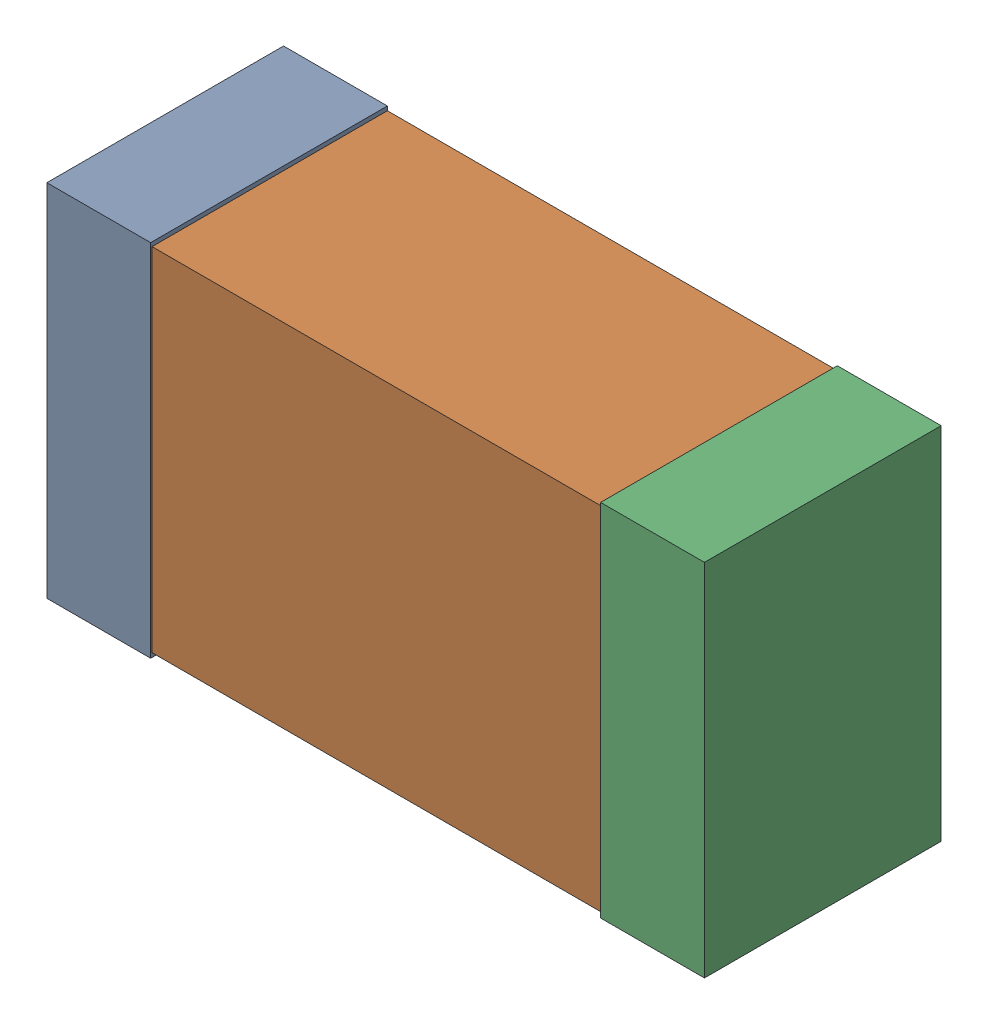
SolidWorks assembly C14_Motor_4Kanaloa_v2.0.0_Motor, configuration Default. Lengths in mm.
Overall size (2.38 1.3 0.85).
6 component instances, 2 part files, 0 mates.
Components (placement in the parent):
- 352877648-1: 352877648 [Default] at (76.799 83.82 0) size (0.38 1.3 0.85)
  - Extruded_14-1: Extruded_14 [Default] at origin size (0.38 1.3 0.85)
- 352877392-1: 352877392 [Default] at (77.799 83.82 0) size (2.2 1.27 0.85)
  - Extruded_15-1: Extruded_15 [Default] at origin size (2.2 1.27 0.85)
- 352877648-2: 352877648 [Default] at (78.799 83.82 0) size (0.38 1.3 0.85)
  - Extruded_14-1: Extruded_14 [Default] at origin size (0.38 1.3 0.85)
